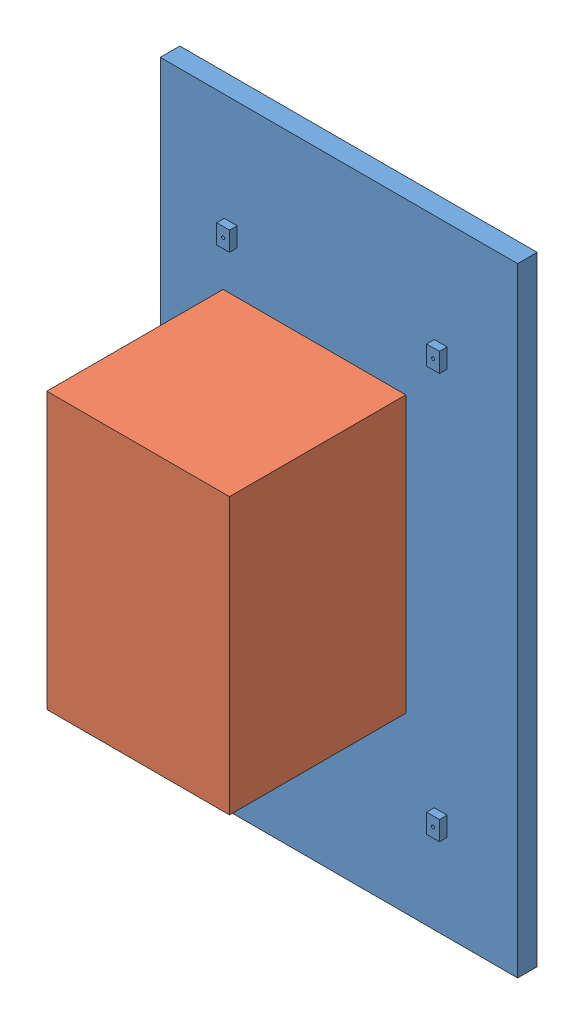
SolidWorks assembly Assem1, configuration Default. Lengths in mm.
Overall size (111.5 193.09 63.5).
2 component instances, 2 part files, 2 mates.
Components (placement in the parent):
- Screen-1: Screen [Default] at (9.8156 56.5814 211.084) size (111.5 193.09 8.5)
- Raspberry Pi-1: Raspberry Pi [Default] at (88.8156 199.0814 219.584) x (-1 0 0) z (0 0 1) size (57 86 55.04)
Mates (geometry in assembly coordinates):
- Coincident7: coincident: circle of Screen-1; circle of Raspberry Pi-1
- Parallel1: parallel aligned: line of Screen-1 through (79.3156 170.5814 219.584) axis (0 1 0); line of Raspberry Pi-1 through (88.8156 113.0814 219.584) axis (0 1 0)
